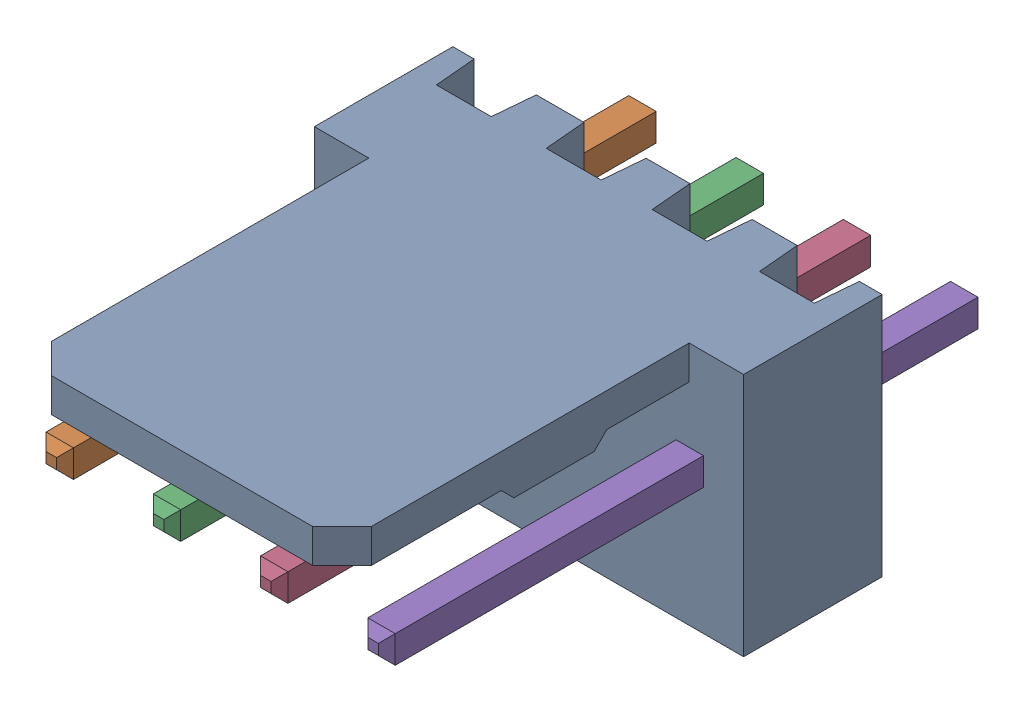
SolidWorks assembly Molex PCB 4 pin v3_5, configuration Predeterminado. Lengths in mm.
Overall size (10.16 5.79 14.92).
5 component instances, 2 part files, 0 mates.
Components (placement in the parent):
- BASE9710016-1: BASE9710016 [Predeterminado] at (2.54 2.895 -8.22) size (10.16 5.79 11.5)
- PINO9710016-1: PINO9710016 [Predeterminado] at (1.27 3.325 -0.72) size (0.65 0.65 14.2)
- PINO9710016-2: PINO9710016 [Predeterminado] at (3.81 3.325 -0.72) size (0.65 0.65 14.2)
- PINO9710016-3: PINO9710016 [Predeterminado] at (6.35 3.325 -0.72) size (0.65 0.65 14.2)
- PINO9710016-4: PINO9710016 [Predeterminado] at (8.89 3.325 -0.72) size (0.65 0.65 14.2)
